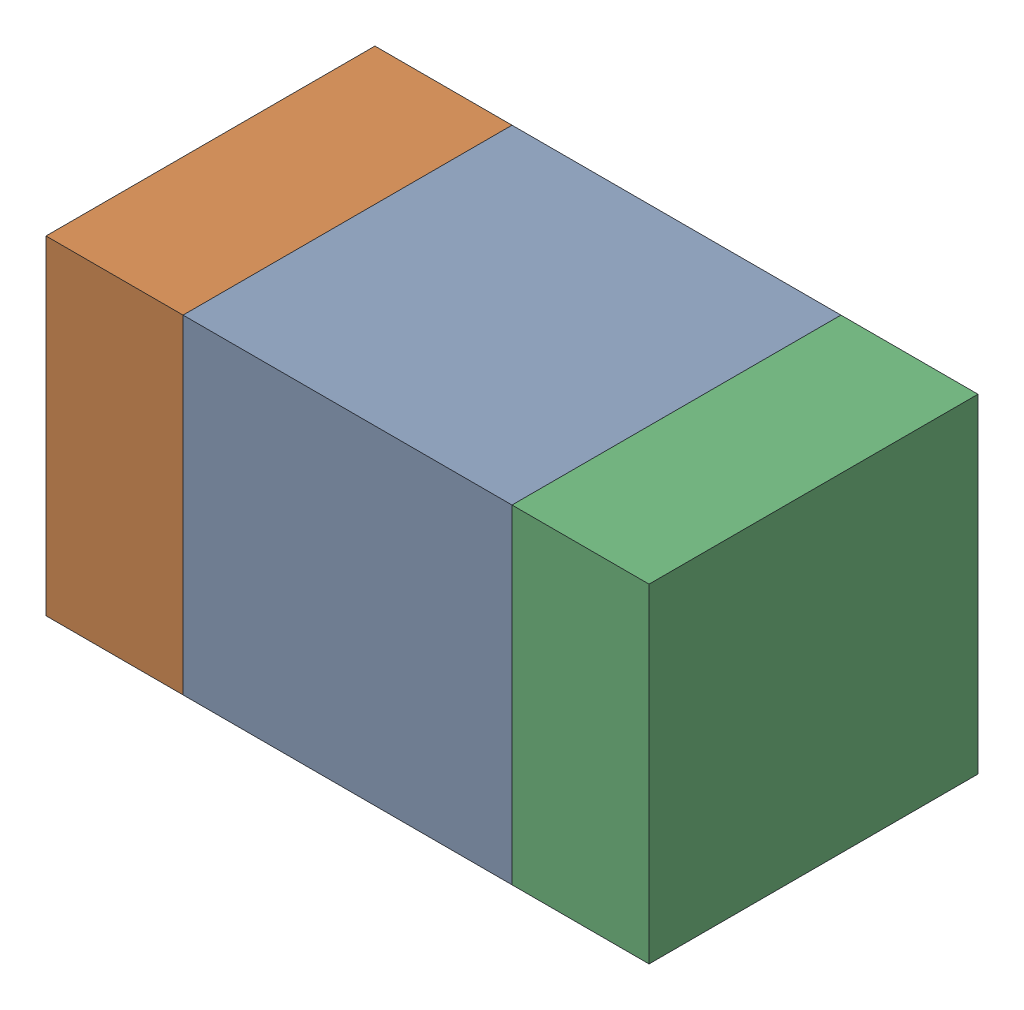
SolidWorks assembly C303_1PCB, configuration Default. Lengths in mm.
Overall size (1.1 0.6 0.6).
6 component instances, 2 part files, 0 mates.
Components (placement in the parent):
- 761606048-1: 761606048 [Default] at (139.9 104.5 0) size (0.6 0.6 0.6)
  - Extruded_9-1: Extruded_9 [Default] at origin size (0.6 0.6 0.6)
- 854785160-1: 854785160 [Default] at (139.475 104.5 0) size (0.25 0.6 0.6)
  - Extruded_19-1: Extruded_19 [Default] at origin size (0.25 0.6 0.6)
- 854785160-2: 854785160 [Default] at (140.325 104.5 0) size (0.25 0.6 0.6)
  - Extruded_19-1: Extruded_19 [Default] at origin size (0.25 0.6 0.6)
